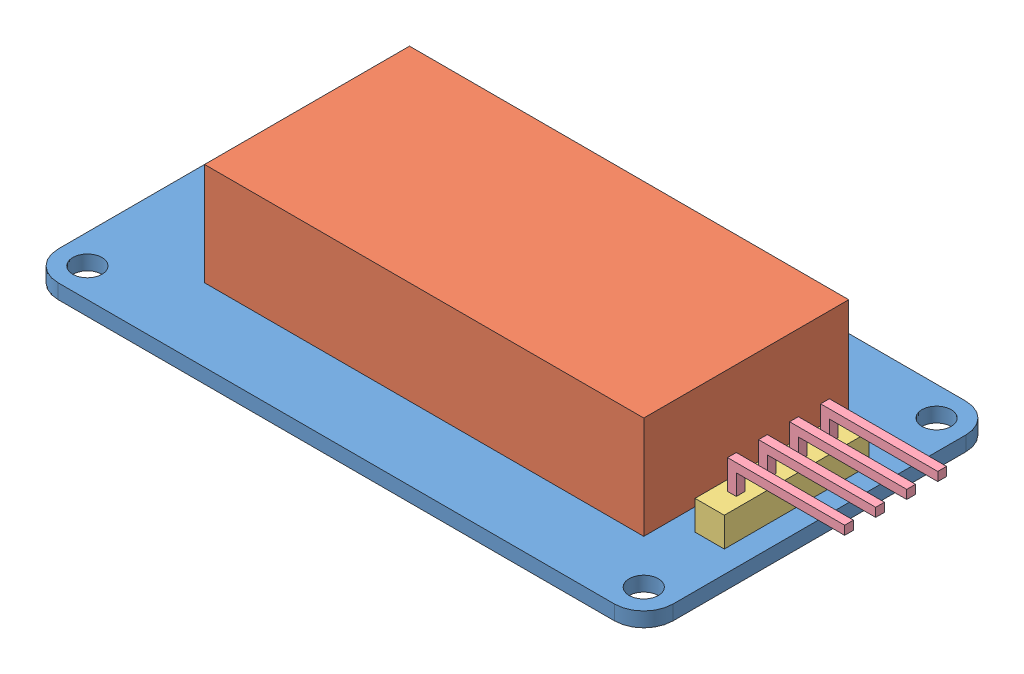
SolidWorks assembly 4-digit Display, configuration Default. Lengths in mm.
Overall size (47.2 8 24).
8 component instances, 4 part files, 6 mates.
Components (placement in the parent):
- PCB-1: PCB [Default] at origin size (42 1 24)
- 7segment display-1: 7segment display [Default] at (1 1 0) size (30 7 14)
- Header-1: Header [Default] at (18.5 1 0.05) size (8.7 4 9.9)
  - Header-Base-1: Header-Base [Default] at origin size (2 2 9.9)
  - Header-Pin-1: Header-Pin [Default] at (0 2 3.13) x (0 0 -1) z (1 0 0) size (0.6 2 8)
  - Header-Pin-2: Header-Pin [Default] at (0 2 1.01) x (0 0 -1) z (1 0 0) size (0.6 2 8)
  - Header-Pin-3: Header-Pin [Default] at (0 2 -1.11) x (0 0 -1) z (1 0 0) size (0.6 2 8)
  - Header-Pin-4: Header-Pin [Default] at (0 2 -3.23) x (0 0 -1) z (1 0 0) size (0.6 2 8)
Mates (geometry in assembly coordinates):
- Coincident1: coincident: plane of PCB-1 through (0 1 0) normal (0 1 0); plane of 7segment display-1 through (1 1 0) normal (0 -1 0)
- Distance1: distance = 5 mm: plane of 7segment display-1 through (-14 8 7) normal (0 0 1); plane of PCB-1 through (-21 1 12) normal (0 0 1)
- Distance2: distance = 7 mm: plane of 7segment display-1 through (-14 8 7) normal (-1 0 0); plane of PCB-1 through (-21 1 12) normal (-1 0 0)
- Coincident6: coincident: plane of PCB-1 through (0 1 0) normal (0 1 0); plane of Header-1/Header-Base-1 through (18.5 1 0.05) normal (0 -1 0)
- Distance3: distance = 7 mm: plane of Header-1/Header-Base-1 through (19.5 3 5) normal (0 0 1); plane of PCB-1 through (-21 1 12) normal (0 0 1)
- Distance4: distance = 1.5 mm: plane of Header-1/Header-Base-1 through (19.5 3 5) normal (1 0 0); line of PCB-1 through (21 1 10) axis (0 0 -1)
